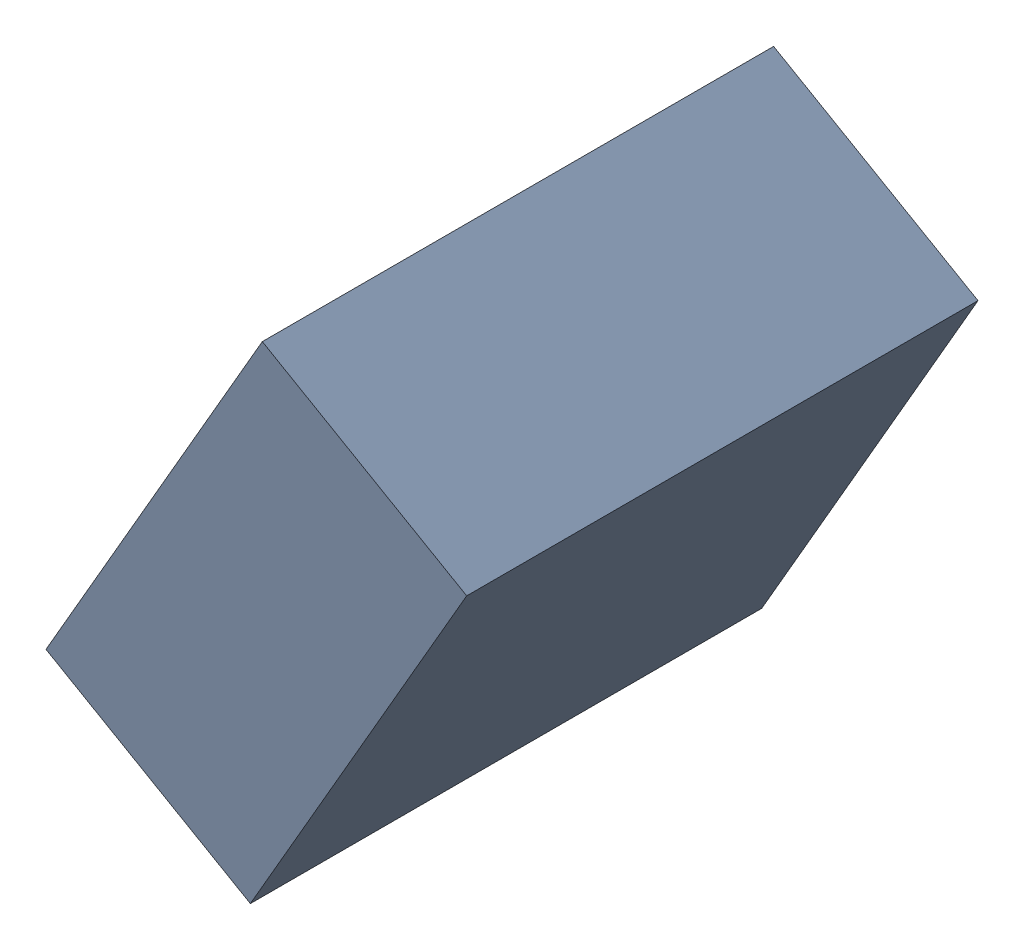
SolidWorks assembly C29_TDA3, configuration Standard. Lengths in mm.
Overall size (1.07 1.25 1.3).
2 component instances, 1 part files, 0 mates.
Components (placement in the parent):
- 885543328-1: 885543328 [Standard] at (49.1171 -30.8179 0) size (1.07 1.25 1.3)
  - Extruded_26-1: Extruded_26 [Standard] at origin size (1.07 1.25 1.3)
